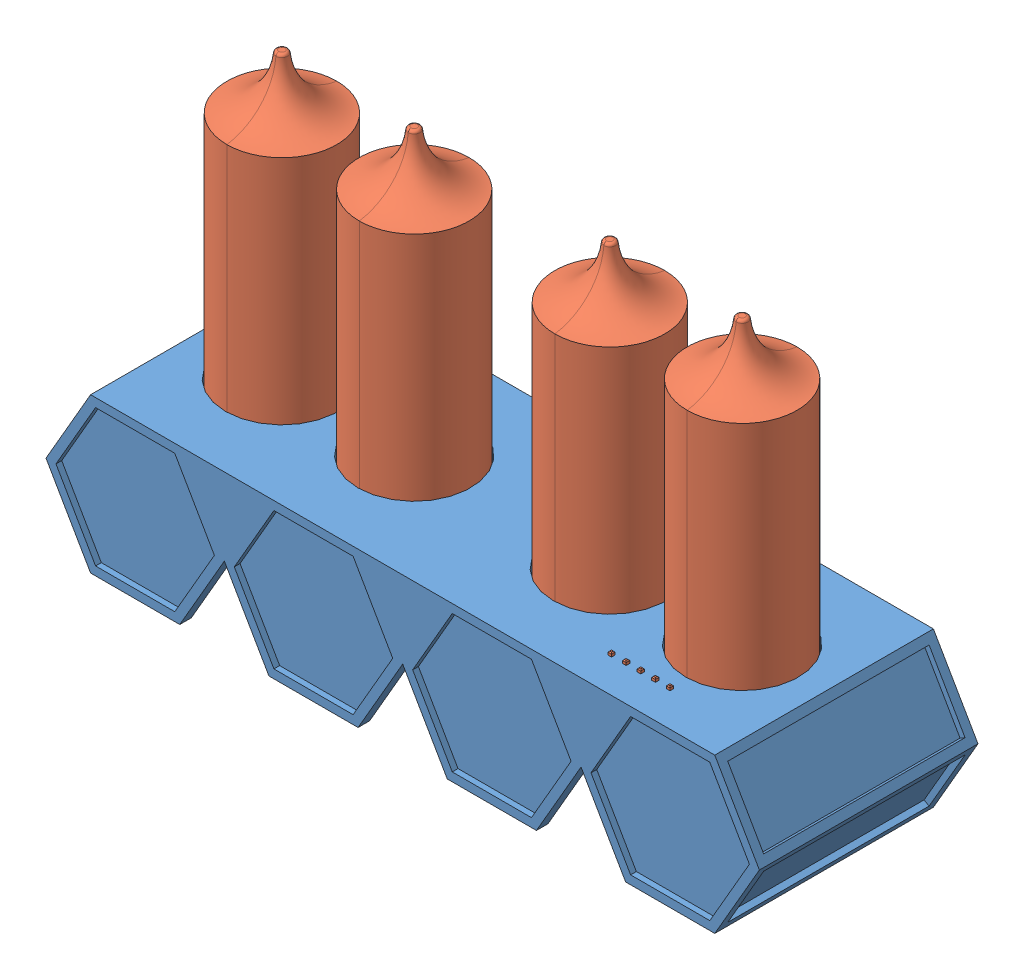
SolidWorks assembly Assem16, configuration Default. Lengths in mm.
Overall size (124 76.4 38).
2 component instances, 2 part files, 3 mates.
Components (placement in the parent):
- Case1-1: Case1 [Default] at (-84.6211 30.5968 -17.8795) size (124 26.85 38)
- PCBV1-1: PCBV1 [Default] at (-138.1211 34.4202 -63.8795) x (1 0 0) z (0 1 0) size (100 30 61.7)
Mates (geometry in assembly coordinates):
- Concentric1: concentric aligned: cylinder of Case1-1 through (1.8789 34.0202 1.1205) axis (0 1 0) radius 9.8; cylinder of PCBV1-1 through (1.8789 93.5702 1.1205) axis (0 1 0) radius 9.55
- Concentric2: concentric aligned: cylinder of Case1-1 through (-78.1211 34.0202 1.1205) axis (0 1 0) radius 9.8; cylinder of PCBV1-1 through (-78.1211 93.5702 1.1205) axis (0 1 0) radius 9.55
- Distance1: distance = 6 mm anti-aligned: plane of PCBV1-1 through (-38.1211 36.0202 1.1205) normal (0 1 0); plane of Case1-1 through (-84.6211 42.0202 20.1205) normal (0 -1 0)
